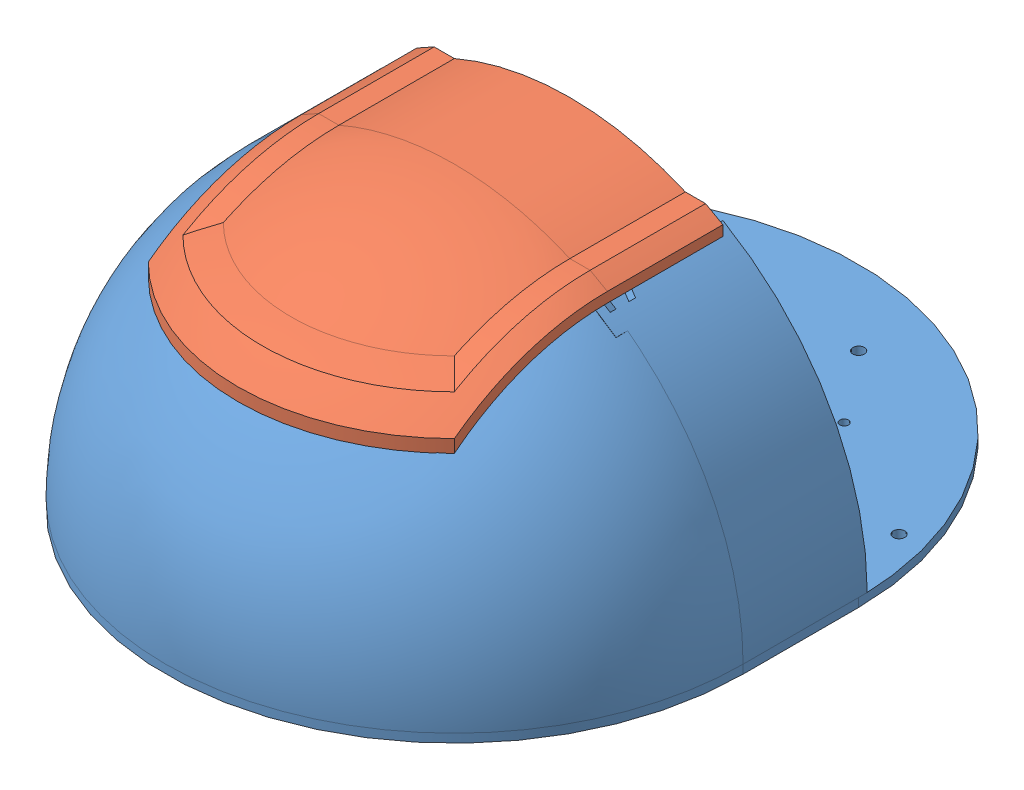
SolidWorks assembly 装配体4, configuration 默认. Lengths in mm.
Overall size (200 103 240).
4 component instances, 4 part files, 9 mates.
Components (placement in the parent):
- 控制器安装盘-1: 控制器安装盘 [默认] at (1.9306 -43.5142 260) size (200 89.6 240)
- 弧盖-1: 弧盖 [默认] at (1.9306 -40.5142 260) size (106 33.8 114.95)
- 控制板托架STM32-1: 控制板托架STM32 [默认] at (1.9306 -13.6674 284.9641) x (1 0 0) z (0 -0.866025 0.5) size (110 4.4 62)
- 控制板托架树莓派-1: 控制板托架树莓派 [默认] at (1.9306 -9.5142 261) x (-1 0 0) z (0 -1 0) size (110 5 62)
Mates (geometry in assembly coordinates):
- 重合1: coincident: plane of 控制器安装盘-1 through (-53.0694 -43.5142 260) normal (1 0 0); plane of 控制板托架树莓派-1 through (-53.0694 5.4858 259) normal (-1 0 0)
- 重合2: coincident: plane of 控制器安装盘-1 through (-53.0694 -24.5142 261) normal (0 1 0); plane of 控制板托架树莓派-1 through (56.9306 -24.5142 259) normal (0 -1 0)
- 重合3: coincident anti-aligned: plane of 控制器安装盘-1 through (-53.0694 -24.5142 261) normal (0 0 -1); plane of 控制板托架树莓派-1 through (1.9306 -9.5142 261) normal (0 0 1)
- 重合4: coincident: plane of 控制器安装盘-1 through (-53.0694 -26.6578 292.4641) normal (0 0.866025 -0.5); plane of 控制板托架STM32-1 through (-53.0694 -25.6578 294.1962) normal (0 -0.866025 0.5)
- 重合5: coincident: plane of 控制器安装盘-1 through (-53.0694 -43.5142 260) normal (1 0 0); plane of 控制板托架STM32-1 through (-53.0694 0.323 279.1962) normal (-1 0 0)
- 重合6: coincident anti-aligned: plane of 控制器安装盘-1 through (-53.0694 -26.6578 292.4641) normal (0 0.5 0.866025); plane of 控制板托架STM32-1 through (1.9306 -13.6674 284.9641) normal (0 -0.5 -0.866025)
- 重合7: coincident: plane of 控制器安装盘-1 through (51.9306 59.4858 260) normal (-1 0 0); plane of 弧盖-1 through (51.9306 -40.5142 220) normal (1 0 0)
- 重合8: coincident: plane of 控制器安装盘-1 through (1.9306 -43.5142 220) normal (0 0 1); plane of 弧盖-1 through (1.9306 -40.5142 220) normal (0 0 -1)
- 重合9: coincident aligned: line of 控制器安装盘-1 through (-48.0694 46.0884 217) axis (0 0 1); line of 弧盖-1 through (-48.0694 46.0884 220) axis (0 0 1)
